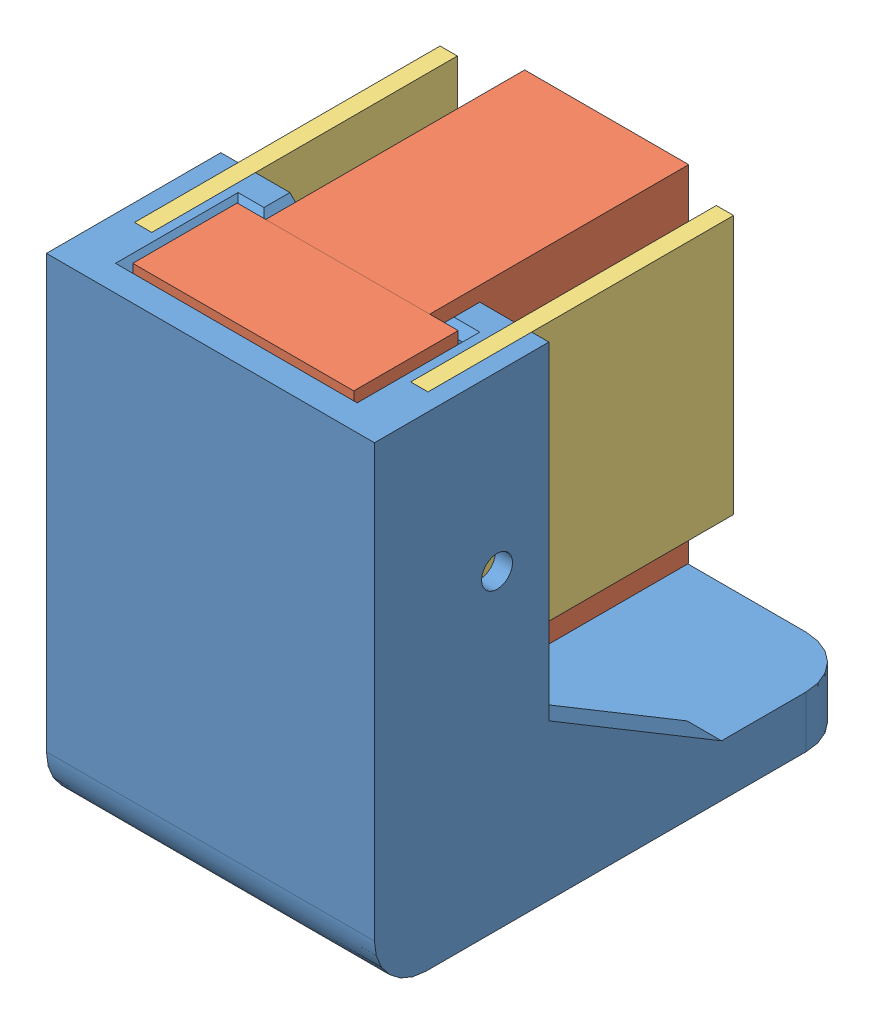
SolidWorks assembly 毛刷装配体2左, configuration 默认. Lengths in mm.
Overall size (28.3 28 28).
4 component instances, 3 part files, 9 mates.
Components (placement in the parent):
- 毛刷固定座2-1: 毛刷固定座2 [默认] at (-1.759 -10.1414 29.5) size (28.3 28 28)
- 金属毛刷-1: 金属毛刷 [默认] at (-1.859 -5.1414 27.5) size (12.8 20 21.05)
- 铁氟龙板-1: 铁氟龙板 [默认] at (-9.259 7.3586 16.55) x (0 1 0) z (0 0 1) size (15 1 17.7)
- 铁氟龙板-2: 铁氟龙板 [默认] at (6.741 7.3586 16.55) x (0 1 0) z (0 0 1) size (15 1 17.7)
Mates (geometry in assembly coordinates):
- 重合1: coincident anti-aligned: plane of 毛刷固定座2-1 through (-8.259 14.8586 27.5) normal (0 0 -1); plane of 金属毛刷-1 through (-8.259 14.8586 27.5) normal (0 0 1)
- 重合2: coincident aligned: plane of 毛刷固定座2-1 through (-1.759 14.8586 29.5) normal (0 1 0); plane of 金属毛刷-1 through (-1.859 14.8586 27.5) normal (0 1 0)
- 重合3: coincident anti-aligned: plane of 毛刷固定座2-1 through (-8.259 14.8586 21.4) normal (1 0 0); plane of 金属毛刷-1 through (-8.259 14.8586 21.45) normal (-1 0 0)
- 重合4: coincident anti-aligned: plane of 毛刷固定座2-1 through (-9.259 -0.1414 25.4) normal (0 0 -1); plane of 铁氟龙板-1 through (-10.259 -0.1414 25.4) normal (0 0 1)
- 重合5: coincident anti-aligned: plane of 毛刷固定座2-1 through (-10.259 -0.1414 25.4) normal (1 0 0); plane of 铁氟龙板-1 through (-10.259 7.3586 16.55) normal (-1 0 0)
- 重合6: coincident anti-aligned: plane of 毛刷固定座2-1 through (-1.759 -0.1414 29.5) normal (0 1 0); plane of 铁氟龙板-1 through (-10.259 -0.1414 7.7) normal (0 -1 0)
- 重合7: coincident anti-aligned: plane of 毛刷固定座2-1 through (5.741 -0.1414 25.4) normal (0 0 -1); plane of 铁氟龙板-2 through (5.741 -0.1414 25.4) normal (0 0 1)
- 重合8: coincident anti-aligned: plane of 毛刷固定座2-1 through (5.741 -0.1414 19.4) normal (1 0 0); plane of 铁氟龙板-2 through (5.741 7.3586 16.55) normal (-1 0 0)
- 重合9: coincident anti-aligned: plane of 毛刷固定座2-1 through (-1.759 -0.1414 29.5) normal (0 1 0); plane of 铁氟龙板-2 through (5.741 -0.1414 7.7) normal (0 -1 0)
